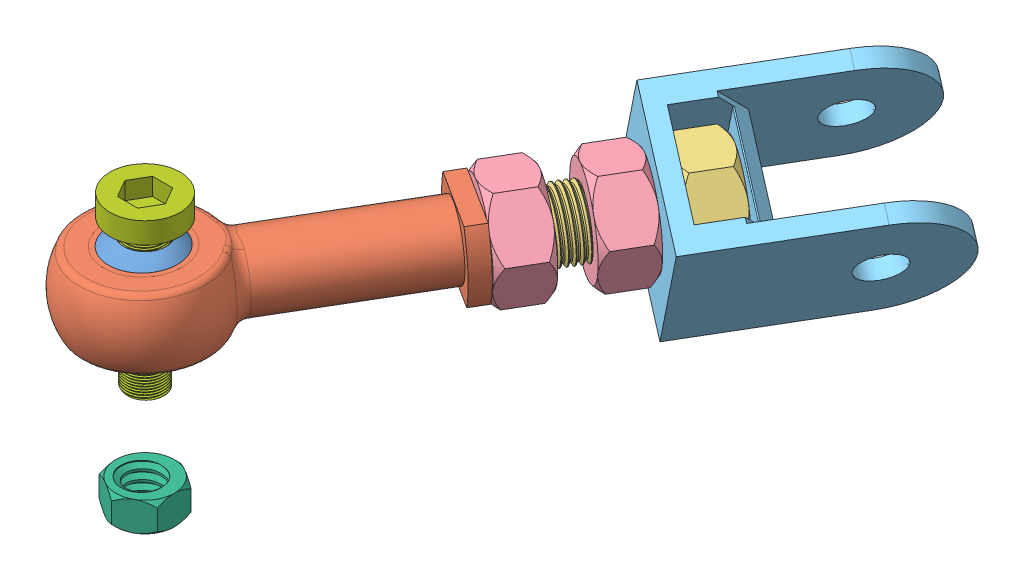
SolidWorks assembly End join bearing, configuration Default. Lengths in mm.
Overall size (70.69 44.06 92.03).
8 component instances, 7 part files, 13 mates.
Components (placement in the parent):
- Ball-1: Ball [Default] at (7.6184 7.2469 9.5238) size (14 12.65 14)
- connector part-1: connector part [Default] at (13.0163 7.5166 1.1101) x (0.539787 0.026969 -0.84137) z (0.841503 0.009357 0.540172) size (44.87 10.62 20)
- M8 Bolt for end joint-1: M8 Bolt for end joint [Default] at (38.836 8.8066 -39.1354) x (0.021454 -0.999603 -0.018277) z (-0.539787 -0.026969 0.84137) size (13.33 16.93 49.17)
- M8 Nut-1: M8 Nut [Default] at (28.0403 8.2673 -22.308) x (0.784922 -0.377288 0.491479) z (-0.539787 -0.026969 0.84137) size (13.33 16.93 7.25)
- M8 Nut-2: M8 Nut [Default] at (33.888 8.5594 -31.4229) x (0.791703 -0.355923 0.496514) z (-0.539787 -0.026969 0.84137) size (13.33 16.93 7.25)
- connector to rocker-1: connector to rocker [Default] at (49.0201 4.0189 -38.8961) x (-0.539787 -0.026969 0.84137) z (-0.402184 -0.869774 -0.285904) size (32 20 20)
- M5 nut-1: M5 nut [Default] at (7.6224 -18.3986 9.5221) x (1 0 0) z (0 1 0) size (8.33 10.58 5.06)
- M5 bolt for end joint-3: M5 bolt for end joint [Default] at (7.6184 17.3007 9.5238) x (0.867008 0 -0.498294) z (0 -1 0) size (10 10 24.07)
Mates (geometry in assembly coordinates):
- Concentric1: concentric: sphere of Ball-1; sphere of connector part-1
- LimitAngle1: limit planar angle = 0.02855 rad: axis of connector part-1 through (7.4904 12.9463 9.6244) axis (0.022441 -0.999592 -0.017644); axis of Ball-1 through (7.6184 11.9459 9.5238) axis (0 -1 0)
- Distance1: distance = 2 mm: plane of M8 Bolt for end joint-1 through (14.3657 7.584 -0.9933) normal (-0.539787 -0.026969 0.84137); plane of connector part-1 through (15.4453 7.638 -2.6761) normal (0.539787 0.026969 -0.84137)
- Coincident4: coincident: axis of connector part-1 through (15.7692 7.6542 -3.1809) axis (0.539787 0.026969 -0.84137); axis of M8 Bolt for end joint-1 through (39.3157 8.8306 -39.8831) axis (0.539787 0.026969 -0.84137)
- Coincident5: coincident: axis of M8 Bolt for end joint-1 through (14.3657 7.584 -0.9933) axis (0.539787 0.026969 -0.84137); axis of M8 Nut-2 through (35.6873 8.6493 -34.2274) axis (-0.539787 -0.026969 0.84137)
- Coincident6: coincident: axis of M8 Bolt for end joint-1 through (14.3657 7.584 -0.9933) axis (0.539787 0.026969 -0.84137); axis of M8 Nut-1 through (29.8396 8.3572 -25.1126) axis (-0.539787 -0.026969 0.84137)
- Coincident7: coincident: plane of connector part-1 through (22.2439 8.1329 -22.0693) normal (0.539787 0.026969 -0.84137); plane of M8 Nut-1 through (26.241 8.1774 -19.5035) normal (-0.539787 -0.026969 0.84137)
- Coincident8: coincident: axis of M8 Bolt for end joint-1 through (39.3157 8.8306 -39.8831) axis (0.539787 0.026969 -0.84137); axis of connector to rocker-1 through (37.0368 8.7167 -36.3309) axis (-0.539787 -0.026969 0.84137)
- Coincident9: coincident: plane of M8 Bolt for end joint-1 through (37.0368 8.7167 -36.3309) normal (-0.539787 -0.026969 0.84137); plane of connector to rocker-1 through (29.1928 5.9788 -41.451) normal (0.539787 0.026969 -0.84137)
- Parallel1: parallel: plane of M8 Bolt for end joint-1 through (33.6547 15.3493 -38.2881) normal (-0.739512 0.492713 -0.458646); plane of connector to rocker-1 through (29.1928 5.9788 -41.451) normal (0.739512 -0.492713 0.458646)
- Coincident10: coincident: plane of M8 Nut-2 through (35.6873 8.6493 -34.2274) normal (0.539787 0.026969 -0.84137); plane of connector to rocker-1 through (24.2703 4.8787 -41.6729) normal (-0.539787 -0.026969 0.84137)
- Coincident19: coincident: axis of Ball-1 through (7.6184 11.9459 9.5238) axis (0 -1 0); axis of M5 bolt for end joint-3 through (7.6184 -5.0193 9.5238) axis (0 1 0)
- Coincident20: coincident: axis of M5 nut-1 through (7.6184 -18.9746 9.5238) axis (0 -1 0); axis of M5 bolt for end joint-3 through (7.6184 -5.0193 9.5238) axis (0 1 0)
